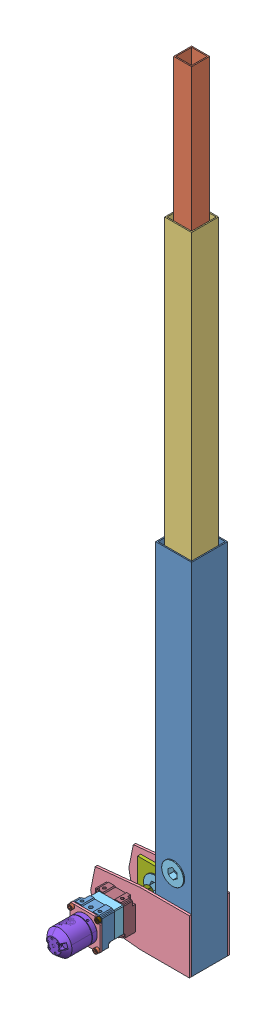
SolidWorks assembly Arm assembly in arm folder, configuration Default. Lengths in mm.
Overall size (139.7 1102.82 151.98).
41 component instances, 26 part files, 25 mates.
Components (placement in the parent):
- 30 by 2 by 2 extrusino-1: 30 by 2 by 2 extrusino [Default] at (178.6408 34.1326 640.8475) size (50.8 508 50.8)
- 30 in 1 by 1 extrusion-1: 30 in 1 by 1 extrusion [Default] at (191.3408 374.9527 602.7475) x (0 0 1) z (-1 0 0) size (25.4 762 25.4)
- 30 in 1.5 by 1.5 extrusion-1: 30 in 1.5 by 1.5 extrusion [Default] at (184.9908 178.0872 634.4975) size (38.1 762 38.1)
- Motor mount arm bracket-1: Motor mount arm bracket [Default] at (179.2878 74.1525 586.8725) x (0 1 0) z (0 0 1) size (76.2 139.7 3.17)
- Motor mount arm bracket-2: Motor mount arm bracket [Default] at (179.2878 70.3128 644.0225) x (0 -1 0) z (0 0 -1) size (76.2 139.7 3.17)
- Half inch flange bearing.step-2: Half inch flange bearing.step [Default] at (132.0826 72.2326 588.2161) x (0.995907 0.090389 0) z (0 0 1) size (31.12 31.12 7.93)
- Motor mount arm square-1: Motor mount arm square [Default] at (123.7934 77.1757 640.8475) x (0 -1 0) z (0 0 -1) size (50.8 50.8 3.17)
- Motor mount arm square .18in-1: Motor mount arm square .18in [Default] at (138.585 78.5996 594.6195) x (-1 0 0) z (0 0 -1) size (50.8 50.8 4.57)
- REV Neo 550-1: REV Neo 550 [Default] at (132.0826 72.2326 682.8475) x (0 0 1) z (0.285166 -0.958478 0) size (56.01 42.91 43.01)
- gearbox for rev neo 550-2: gearbox for rev neo 550 [Default] at (132.0826 94.4576 660.6475) x (0 0 -1) z (-1 0 0) size (97.9 49.04 49.3)
  - VersaPlanetary v2 Single Stage 10_1 with BAG .step-1: VersaPlanetary v2 Single Stage 10_1 with BAG .step [Default] at origin size (97.9 49.04 49.3)
    - 217-2820 Rev1_Public.step-1: 217-2820 Rev1_Public.step [Default] at (-4.6546 22.225 0) x (0 -0.456494 0.889726) z (-1 0 0) size (39.22 38.88 17.4)
      - 217-2625-100.step-1: 217-2625-100.step [Default] at origin size (39.22 38.88 12.7)
        - 217-2625-008 Rev1.step-1: 217-2625-008 Rev1.step [Default] at origin size (34.7 34.7 4.7)
        - 217-2625-010 Rev1.step-1: 217-2625-010 Rev1.step [Default] at (0 10.193 3.65) x (0.999813 0.019336 0) z (0 0 1) size (4 4 12)
        - 217-2625-010 Rev1.step-2: 217-2625-010 Rev1.step [Default] at (8.691 -5.3258 3.65) size (4 4 12)
        - 217-2625-010 Rev1.step-3: 217-2625-010 Rev1.step [Default] at (-8.691 -5.3258 3.65) size (4 4 12)
        - 217-2625-005 Rev1_Planet_Revolving_Follower01.step-1: 217-2625-005 Rev1_Planet_Revolving_Follower01.step [Default] at (8.691 -5.3258 6.35) x (0.932816 0.360354 0) z (0 0 1) size (16.89 16.89 8)
        - 217-2625-005 Rev1_Planet_Revolving_Follower01.step-2: 217-2625-005 Rev1_Planet_Revolving_Follower01.step [Default] at (-8.691 -5.3258 6.35) x (-0.932788 -0.360426 0) z (0 0 1) size (16.89 16.89 8)
        - 217-2625-005 Rev1_Planet_Revolving_Follower01.step-3: 217-2625-005 Rev1_Planet_Revolving_Follower01.step [Default] at (0 10.193 6.35) x (0.893583 0.448898 0) z (0 0 1) size (16.89 16.89 8)
      - 217-2625-007 Rev1_Public.step-1: 217-2625-007 Rev1_Public.step [Default] at (0 0 6.7) x (0.992772 0.120019 0) z (0 0 1) size (15.27 15.27 12.7)
    - 217-2625-026 Rev1.step-1: 217-2625-026 Rev1.step [Default] at (-6.5 22.225 0) x (0 -1 0) z (-1 0 0) size (44.45 42 18.12)
    - 217-2742-001 Rev4.step-1: 217-2742-001 Rev4.step [Default] at (0.2002 22.225 0) x (1 0 0) z (0 -0.092627 0.995701) size (7 28 28)
    - 217-2742-001 Rev4.step-2: 217-2742-001 Rev4.step [Default] at (8.2002 22.225 0) size (7 28 28)
    - 217-2625-017 Rev1_9714K61.step-1: 217-2625-017 Rev1_9714K61.step [Default] at (7.42 22.3002 -0.342) x (0 0.56703 0.823697) z (0 -0.823697 0.56703) size (28.51 4.98 27.43)
    - 217-2625-003 Rev1.step-1: 217-2625-003 Rev1.step [Default] at (7.4478 22.225 0) x (0 -1 0) z (1 0 0) size (17 17 64.11)
    - 217-2625-018 Rev1_98541A410.step-1: 217-2625-018 Rev1_98541A410.step [Default] at (-0.7046 22.225 0) x (1 0 0) z (0 -0.017452 0.999848) size (1 19.6 17.4)
    - 832-1750-Ring-Gear-Screw_SSA0832-0500ZC.step-1: 832-1750-Ring-Gear-Screw_SSA0832-0500ZC.step [Default] at (-30.7 4.725 -17.5) x (0 0.997447 0.071411) z (0 -0.071411 0.997447) size (6.73 48.51 6.73)
    - 832-1750-Ring-Gear-Screw_SSA0832-0500ZC.step-2: 832-1750-Ring-Gear-Screw_SSA0832-0500ZC.step [Default] at (-30.7 39.725 17.5) x (0 0.005929 0.999982) z (0 -0.999982 0.005929) size (6.73 48.51 6.73)
    - 217-2625-025 Rev1.step-1: 217-2625-025 Rev1.step [Default] at (-23.2 22.225 0) x (0 -1 0) z (-1 0 0) size (44.45 42 18)
    - 217-4649-002 Rev1_SSA0832-0500ZC.step-1: 217-4649-002 Rev1_SSA0832-0500ZC.step [Default] at (-33.7 4.2645 17.9605) x (0 0.33842 -0.940995) z (0 0.940995 0.33842) size (6.73 16.76 6.73)
    - 217-4649-002 Rev1_SSA0832-0500ZC.step-2: 217-4649-002 Rev1_SSA0832-0500ZC.step [Default] at (-33.7 40.1855 -17.9605) x (0 -0.308932 -0.951084) z (0 0.951084 -0.308932) size (6.73 16.76 6.73)
    - 217-4649-006 Rev1_SSA0004-008BA.step-1: 217-4649-006 Rev1_SSA0004-008BA.step [Default] at (-30.7 22.225 12.5) x (0 0.5 -0.866025) z (0 -0.866025 -0.5) size (7 14 7)
    - 217-4649-006 Rev1_SSA0004-008BA.step-2: 217-4649-006 Rev1_SSA0004-008BA.step [Default] at (-30.7 22.225 -12.5) x (0 -0.5 0.866025) z (0 0.866025 0.5) size (7 14 7)
    - 217-2822-003 Rev4.step-1: 217-2822-003 Rev4.step [Default] at (-32.2 22.225 0) x (0 -1 0) z (-1 0 0) size (42 42 4.8)
    - 217-2816-001 Rev1.step-1: 217-2816-001 Rev1.step [Default] at (-6.35 22.225 0) x (0 -1 0) z (1 0 0) size (42 42 14.51)
    - 217-4649-001 Rev1.step-1: 217-4649-001 Rev1.step [Default] at (-20.046 22.225 0) x (0 -1 0) z (1 0 0) size (18 18 13)
    - 217-4649-007 Rev1_94105A824.step-1: 217-4649-007 Rev1_94105A824.step [Default] at (-25.521 22.225 -6.7835) x (-0.996104 -0.088191 0) z (0 0 -1) size (4.83 4.83 4.77)
    - 217-2625-011 Rev1.step-1: 217-2625-011 Rev1.step [Default] at (-24.7818 22.225 0) x (0 0 1) z (0 -1 0) size (8.01 7.5 7.94)
- Half inch flange bearing.step-3: Half inch flange bearing.step [Default] at (204.0408 148.4326 596.4508) x (-0.257655 0.966237 0) z (0 0 -1) size (31.12 31.12 7.93)
- Half inch flange bearing.step-4: Half inch flange bearing.step [Default] at (204.0408 148.4326 634.4441) x (0.083704 -0.996491 0) z (0 0 1) size (31.12 31.12 7.93)
Mates (geometry in assembly coordinates):
- Width1: width aligned: plane of 30 by 2 by 2 extrusino-1 through (227.8406 542.1326 591.6477) normal (-1 0 0); plane of 30 in 1.5 by 1.5 extrusion-1 through (180.241 542.1326 591.6477) normal (1 0 0); plane of 30 by 2 by 2 extrusino-1 through (184.9908 940.0872 634.4975) normal (-1 0 0); plane of 30 in 1.5 by 1.5 extrusion-1 through (223.0908 940.0872 634.4975) normal (1 0 0)
- Width2: width anti-aligned: plane of 30 by 2 by 2 extrusino-1 through (180.241 542.1326 591.6477) normal (0 0 1); plane of 30 in 1.5 by 1.5 extrusion-1 through (180.241 542.1326 639.2473) normal (0 0 -1); plane of 30 by 2 by 2 extrusino-1 through (184.9908 940.0872 596.3975) normal (0 0 -1); plane of 30 in 1.5 by 1.5 extrusion-1 through (184.9908 940.0872 634.4975) normal (0 0 1)
- Width3: width anti-aligned: plane of 30 in 1.5 by 1.5 extrusion-1 through (186.591 940.0872 597.9977) normal (0 0 1); plane of 30 in 1 by 1 extrusion-1 through (186.591 940.0872 632.8973) normal (0 0 -1); plane of 30 in 1.5 by 1.5 extrusion-1 through (191.3408 1136.9527 602.7475) normal (0 0 -1); plane of 30 in 1 by 1 extrusion-1 through (191.3408 1136.9527 628.1475) normal (0 0 1)
- Width4: width anti-aligned: plane of 30 in 1.5 by 1.5 extrusion-1 through (221.4906 940.0872 597.9977) normal (-1 0 0); plane of 30 in 1 by 1 extrusion-1 through (186.591 940.0872 597.9977) normal (1 0 0); plane of 30 in 1.5 by 1.5 extrusion-1 through (216.7408 1136.9527 602.7475) normal (1 0 0); plane of 30 in 1 by 1 extrusion-1 through (191.3408 1136.9527 602.7475) normal (-1 0 0)
- Coincident1: coincident anti-aligned: plane of 30 by 2 by 2 extrusino-1 through (178.6408 542.1326 640.8475) normal (0 0 1); plane of Motor mount arm bracket-2 through (179.2878 70.3128 640.8475) normal (0 0 -1)
- Coincident2: coincident aligned: plane of 30 by 2 by 2 extrusino-1 through (229.4408 542.1326 640.8475) normal (1 0 0); plane of Motor mount arm bracket-2 through (229.4408 70.3128 640.8475) normal (1 0 0)
- Coincident3: coincident aligned: plane of 30 by 2 by 2 extrusino-1 through (178.6408 34.1326 640.8475) normal (0 -1 0); plane of Motor mount arm bracket-2 through (179.2878 34.1326 640.8475) normal (0 -1 0)
- Coincident4: coincident anti-aligned: plane of 30 by 2 by 2 extrusino-1 through (178.6408 542.1326 590.0475) normal (0 0 -1); plane of Motor mount arm bracket-1 through (179.2878 74.1525 590.0475) normal (0 0 1)
- Coincident5: coincident aligned: plane of 30 by 2 by 2 extrusino-1 through (229.4408 542.1326 640.8475) normal (1 0 0); plane of Motor mount arm bracket-1 through (229.4408 74.1525 590.0475) normal (1 0 0)
- Coincident6: coincident aligned: plane of 30 by 2 by 2 extrusino-1 through (178.6408 34.1326 640.8475) normal (0 -1 0); plane of Motor mount arm bracket-1 through (179.2878 34.1326 590.0475) normal (0 -1 0)
- Concentric2: concentric anti-aligned: cylinder of Motor mount arm bracket-1 through (132.0826 72.2326 586.8725) axis (0 0 1) radius 14.2875; cylinder of Half inch flange bearing.step-2 through (132.0826 72.2326 596.1435) axis (0 0 -1) radius 14.2875
- Concentric3: concentric aligned: cylinder of Motor mount arm bracket-2 through (132.0826 72.2326 644.0225) axis (0 0 -1) radius 14.2875; cylinder of Motor mount arm square-1 through (132.0826 72.2326 640.8475) axis (0 0 -1) radius 14.2875
- Coincident12: coincident anti-aligned: plane of Motor mount arm bracket-1 through (179.2878 74.1525 590.0475) normal (0 0 1); plane of Motor mount arm square .18in-1 through (138.585 78.5996 590.0475) normal (0 0 -1)
- Concentric4: concentric aligned: cylinder of Motor mount arm bracket-1 through (132.0826 72.2326 586.8725) axis (0 0 1) radius 14.2875; cylinder of Motor mount arm square .18in-1 through (132.0826 72.2326 590.0475) axis (0 0 1) radius 14.2875
- Parallel2: parallel anti-aligned: plane of Motor mount arm bracket-1 through (229.4408 74.1525 590.0475) normal (1 0 0); plane of Motor mount arm square .18in-1 through (106.6826 97.6326 590.0475) normal (-1 0 0)
- Coincident14: coincident anti-aligned: plane of Half inch flange bearing.step-2 through (145.9954 73.4954 594.6195) normal (0 0 -1); plane of Motor mount arm square .18in-1 through (138.585 78.5996 594.6195) normal (0 0 1)
- Coincident16: coincident anti-aligned: plane of Motor mount arm bracket-2 through (179.2878 70.3128 644.0225) normal (0 0 1); plane of gearbox for rev neo 550-2/VersaPlanetary v2 Single Stage 10_1 with BAG .step-1/217-2625-026 Rev1.step-1 through (109.8576 50.0076 644.0225) normal (0 0 -1)
- Concentric5: concentric anti-aligned: cylinder of Motor mount arm bracket-2 through (132.0826 72.2326 644.0225) axis (0 0 -1) radius 14.2875; cylinder of gearbox for rev neo 550-2/VersaPlanetary v2 Single Stage 10_1 with BAG .step-1/217-2625-026 Rev1.step-1 through (132.0826 72.2326 644.0225) axis (0 0 1) radius 13.995
- Concentric6: concentric anti-aligned: cylinder of REV Neo 550-1 through (132.0826 72.2326 738.8475) axis (0 0 1) radius 6.5; cylinder of gearbox for rev neo 550-2/VersaPlanetary v2 Single Stage 10_1 with BAG .step-1/217-2822-003 Rev4.step-1 through (132.0826 72.2326 694.3475) axis (0 0 -1) radius 6
- Coincident18: coincident anti-aligned: plane of REV Neo 550-1 through (125.8525 70.3791 694.3475) normal (0 0 -1); plane of gearbox for rev neo 550-2/VersaPlanetary v2 Single Stage 10_1 with BAG .step-1/217-2822-003 Rev4.step-1 through (132.0826 72.2326 694.3475) normal (0 0 1)
- Parallel3: parallel aligned: plane of Motor mount arm bracket-2 through (179.2878 110.3326 640.8475) normal (0 1 0); plane of gearbox for rev neo 550-2/VersaPlanetary v2 Single Stage 10_1 with BAG .step-1/217-2816-001 Rev1.step-1 through (111.0826 93.2326 660.6475) normal (0 1 0)
- Concentric7: concentric anti-aligned: cylinder of 30 by 2 by 2 extrusino-1 through (204.0408 148.4326 586.8725) axis (0 0 1) radius 12.7; cylinder of Half inch flange bearing.step-4 through (204.0408 148.4326 642.3715) axis (0 0 -1) radius 14.2875
- Coincident19: coincident anti-aligned: plane of 30 by 2 by 2 extrusino-1 through (178.6408 542.1326 640.8475) normal (0 0 1); plane of Half inch flange bearing.step-4 through (205.2102 134.5117 640.8475) normal (0 0 -1)
- Concentric8: concentric aligned: cylinder of 30 by 2 by 2 extrusino-1 through (204.0408 148.4326 586.8725) axis (0 0 1) radius 12.7; cylinder of Half inch flange bearing.step-3 through (204.0408 148.4326 588.5235) axis (0 0 1) radius 14.2875
- Coincident22: coincident anti-aligned: plane of 30 by 2 by 2 extrusino-1 through (178.6408 542.1326 590.0475) normal (0 0 -1); plane of Half inch flange bearing.step-3 through (200.4414 161.931 590.0475) normal (0 0 1)
